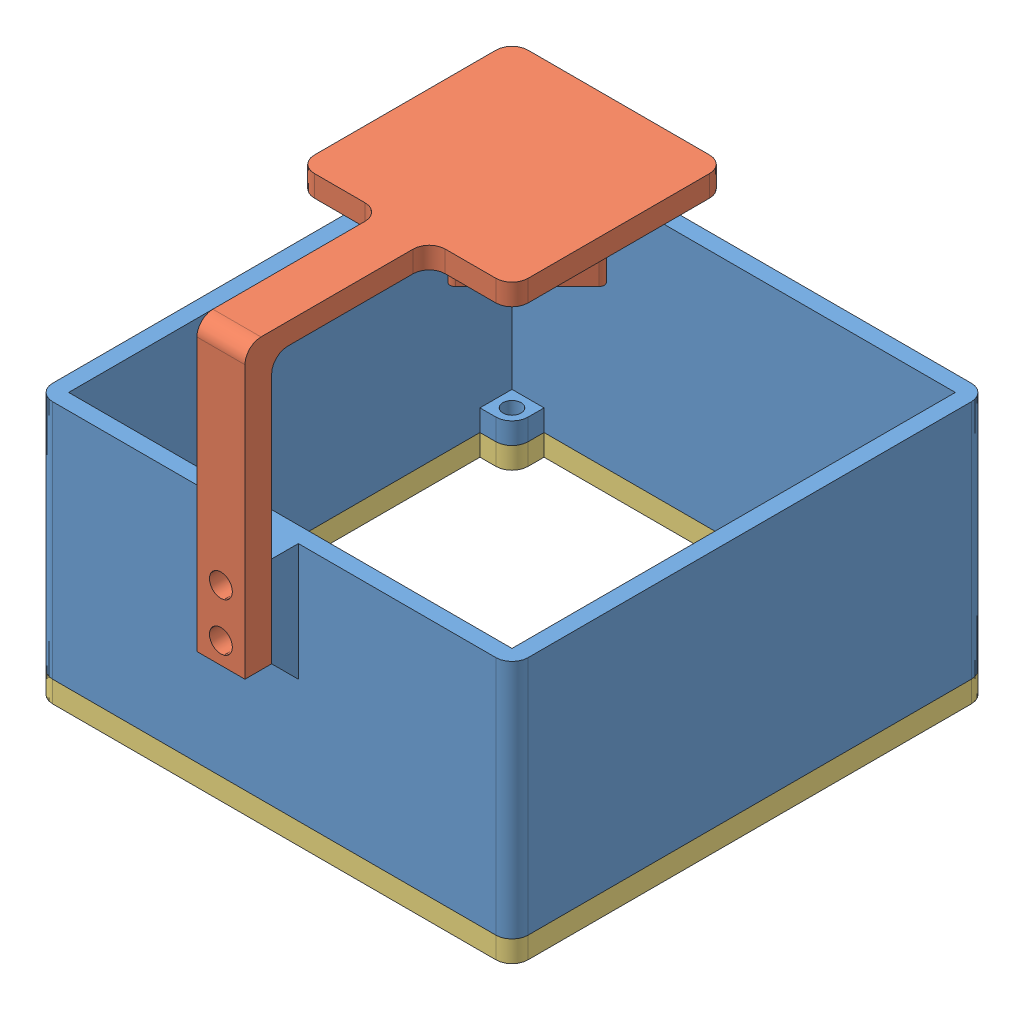
SolidWorks assembly Assem1, configuration Default. Lengths in mm.
Overall size (89 86 99).
3 component instances, 3 part files, 6 mates.
Components (placement in the parent):
- corpo0-1: corpo0 [Default] at (-65.8512 5.0935 49.0979) size (89 45 94)
- poste2-1: poste2 [Default] at (-41.3512 62.5935 24.5979) x (1 0 0) z (0 1 0) size (40 74.5 54)
- tampa1-1: tampa1 [Default] at (-65.8512 -19.4065 49.0979) size (89 4 89)
Mates (geometry in assembly coordinates):
- Coincident1: coincident aligned: plane of corpo0-1 through (23.1488 27.5935 49.0979) normal (1 0 0); plane of tampa1-1 through (23.1488 -17.4065 49.0979) normal (1 0 0)
- Coincident2: coincident anti-aligned: plane of corpo0-1 through (-65.8512 -17.4065 49.0979) normal (0 -1 0); plane of tampa1-1 through (-65.8512 -17.4065 49.0979) normal (0 1 0)
- Coincident3: coincident aligned: plane of corpo0-1 through (-65.8512 27.5935 49.0979) normal (0 0 1); plane of tampa1-1 through (-65.8512 -17.4065 49.0979) normal (0 0 1)
- Width2: width anti-aligned: plane of corpo0-1 through (-65.8512 27.5935 -39.9021) normal (0 0 -1); plane of poste2-1 through (-65.8512 27.5935 49.0979) normal (0 0 1); plane of corpo0-1 through (-41.3512 64.5935 24.5979) normal (0 0 1); plane of poste2-1 through (-41.3512 64.5935 -15.4021) normal (0 0 -1)
- Width3: width anti-aligned: plane of poste2-1 through (-41.3512 64.5935 24.5979) normal (-1 0 0); plane of corpo0-1 through (-1.3512 64.5935 24.5979) normal (1 0 0); plane of poste2-1 through (23.1488 27.5935 49.0979) normal (1 0 0); plane of corpo0-1 through (-65.8512 27.5935 49.0979) normal (-1 0 0)
- Concentric1: concentric anti-aligned: cylinder of corpo0-1 through (-21.3512 14.5935 54.0979) axis (0 0 -1) radius 2.85; cylinder of poste2-1 through (-21.3512 14.5935 54.0979) axis (0 0 1) radius 2.15
